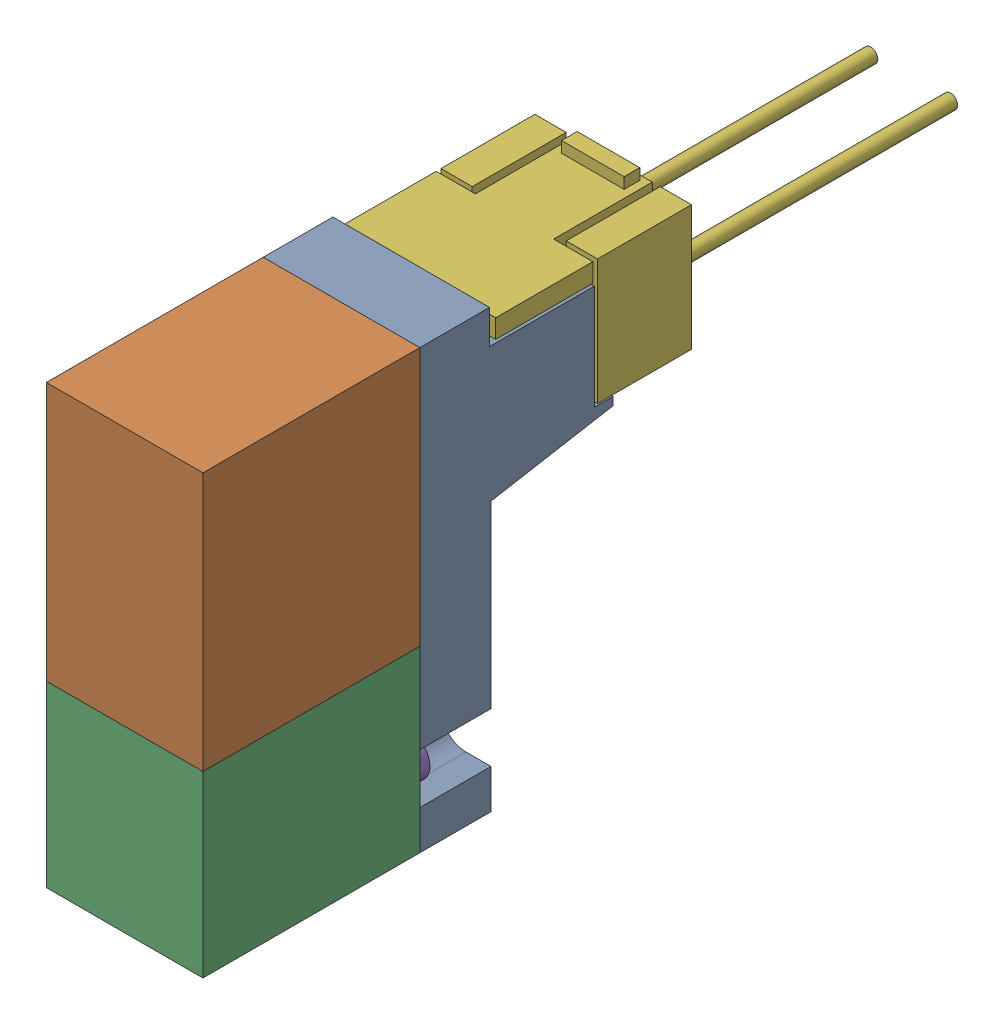
SolidWorks assembly 4GA129-M5-E01-4_D_100000_4G-Coil-SubASSY_01(EDC-E-H), configuration Default. Lengths in mm.
Overall size (10 27.94 50.2).
2 component instances, 2 part files, 0 mates.
Components (placement in the parent):
- 4GA129-M5-E01-4_D_000102_4GcoilEDC_00(Default)-1: 4GA129-M5-E01-4_D_000102_4GcoilEDC_00(Default) [Default] at origin size (10 27.94 26.2)
- 4GA129-M5-E01-4_D_000123_4GSocketAssyE_00(Default)-1: 4GA129-M5-E01-4_D_000123_4GSocketAssyE_00(Default) [Default] at (0 22.17 -25.2) size (10 8.7 31.5)
